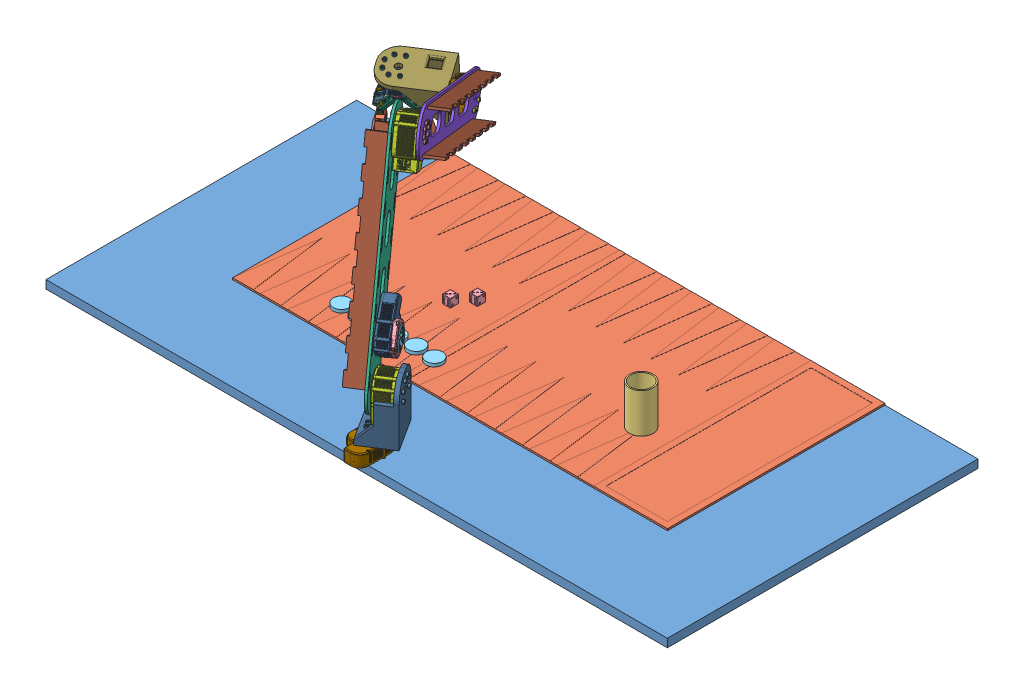
SolidWorks assembly Game Layout, configuration Default. Lengths in mm.
Overall size (1500 678.28 808.49).
129 component instances, 32 part files, 15 mates.
Components (placement in the parent):
- Table-1: Table [Default] at (-44.703 4.5181 13.7258) size (1500 20 750)
- Backgammon Board-1: Backgammon Board [Default] at (-44.703 25.1708 -98.7742) size (1050 4.19 525)
- Dice Cup-1: Dice Cup [Default] at (235.0542 28.3281 -18.6124) size (57.15 95.25 57.15)
- Die_20mm-1: Die_20mm [Default] at (-252.4545 38.3281 -45.2058) size (20 20 20)
- Die_20mm-2: Die_20mm [Default] at (-223.0507 38.3281 -81.2243) size (20 20 20)
- Checker_40mm-1: Checker_40mm [Default] at (-377.9375 28.7091 92.1875) size (40 7.5 40)
- Checker_40mm-2: Checker_40mm [Default] at (-334.5867 28.7091 91.8393) size (40 7.5 40)
- Checker_40mm-3: Checker_40mm [Default] at (-285.5011 28.7091 92.6533) size (40 7.5 40)
- Checker_40mm-4: Checker_40mm [Default] at (-245.1452 28.7091 92.2152) size (40 7.5 40)
- Checker_40mm-5: Checker_40mm [Default] at (-200.0358 28.7091 89.7421) size (40 7.5 40)
- Checker_40mm-6: Checker_40mm [Default] at (-153.1252 28.7091 92.7345) size (40 7.5 40)
- Full Arm-1: Full Arm [Default] at (-368.8864 329.5183 330.3626) x (-0.970024 0.122778 -0.209714) z (0.211313 0 -0.977418) size (657.6 592.09 574.41) (flexible)
  - Upper Arm Link Assembled-1: Upper Arm Link Assembled [Default] at (-318.6686 -146.2323 48.0705) size (548.93 592.09 574.41) (flexible)
    - ME134 Robot Upper Arm-1: ME134 Robot Upper Arm [Default] at (85.1585 219.3336 73.7726) x (0.402286 0.867288 0.293221) z (-0.70231 0.086885 0.706549) size (550 100 5.4)
    - HEBI Robotics-X8-Export-2021-1: HEBI Robotics-X8-Export-2021 [Default] at (-31.6742 11.4014 22.0613) x (-0.122778 -0.992434 0) z (0.70231 -0.086885 -0.706549) size (109.71 73.14 45.05)
    - HEBI Robotics-X8-Export-2021-3: HEBI Robotics-X8-Export-2021 [Default] at (148.6872 401.7633 154.6819) x (-0.402286 -0.867288 -0.293221) z (-0.70231 0.086885 0.706549) size (109.71 73.14 45.05)
    - ME134 Robot Lower Arm-2: ME134 Robot Lower Arm [Default] at (145.9078 392.6031 182.7675) x (0.57097 -0.524014 0.631983) z (-0.70231 0.086885 0.706549) size (550 100 5.4)
    - HEBI Robotics-X5-Export-1: HEBI Robotics-X5-Export [Default] at (401.4098 166.4784 443.3136) x (-0.57097 0.524014 -0.631983) z (0.70231 -0.086885 -0.706549) size (109.71 73.14 31.05)
    - ME134 Robot Base-1: ME134 Robot Base [Default] at (-45.0848 -151.804 61.3535) x (0.122778 0.992434 0) z (-0.70231 0.086885 0.706549) size (135 95 80)
    - HEBI Robotics-X5-Export-2: HEBI Robotics-X5-Export [Default] at (-33.2405 -99.2434 10.05) x (-0.209714 0.025945 -0.977418) z (0.122778 0.992434 0) size (109.71 73.14 31.05)
    - ME134 Arm Flange Short-1: ME134 Arm Flange Short [Default] at (-91.6967 -109.7229 -85.2577) x (0.402286 0.867288 0.293221) z (0.587305 -0.490167 0.644058) size (450 45.8 5.4)
    - ME134 Arm Flange Short-2: ME134 Arm Flange Short [Default] at (-42.0107 -151.191 -30.7704) x (0.402286 0.867288 0.293221) z (0.587305 -0.490167 0.644058) size (450 45.8 5.4)
    - ME134 Arm Flange Short-3: ME134 Arm Flange Short [Default] at (8.7558 456.2815 72.0864) x (0.57097 -0.524014 0.631983) z (-0.425152 -0.847266 -0.318411) size (450 45.8 5.4)
    - ME134 Arm Flange Short-4: ME134 Arm Flange Short [Default] at (482.8327 119.1985 584.7708) x (-0.57097 0.524014 -0.631983) z (0.425152 0.847266 0.318411) size (450 45.8 5.4)
  - Wrist-1: Wrist [Default] at (117.0927 26.9602 501.9879) x (0.711585 0.113815 0.69332) z (-0.020177 0.989695 -0.14176) size (95 153.99 205.81)
    - Wrist Bracket-1: Wrist Bracket [Default] at (0 -68.6171 35.5514) x (0 1 0) z (0 0 1) size (135 95 80)
    - Gripper-1: Gripper [Default] at (-36.5257 46.3543 -1.008) x (0 -1 0) z (1 0 0) size (132.13 195.81 73.14)
      - Hebi Motor with Gripper-1: Hebi Motor with Gripper [Default] at (-48.6457 -21.5594 3.9658) size (128.79 124.31 73.14)
        - HEBI Robotics-A-2143-02-1: HEBI Robotics-A-2143-02 [Default] at (0 4.6253 0) x (0.994658 0 0.103227) z (-0.103227 0 0.994658) size (112.08 105.21 45) (flexible)
          - HEBI Robotics-A-2143-02_PM-2357-02-1: HEBI Robotics-A-2143-02_PM-2357-02 [Default] at (0 30.9247 0) x (0 0 -1) z (1 0 0) size (45 28 44.67)
          - HEBI Robotics-A-2143-02_PM-2358-02-1: HEBI Robotics-A-2143-02_PM-2358-02 [Default] at (-30.4569 31.8574 0) x (0 0 -1) z (0.926102 -0.377274 0) size (23 26 33)
          - HEBI Robotics-A-2143-02_PM-2358-02-2: HEBI Robotics-A-2143-02_PM-2358-02 [Default] at (30.456 31.8595 0) x (0 0 1) z (-0.926098 -0.377283 0) size (23 26 33)
          - HEBI Robotics-A-2143-02_PM-2359-02-1: HEBI Robotics-A-2143-02_PM-2359-02 [Default] at (20.1262 54.8052 0) x (0 0 1) z (0.689702 0.724093 0) size (23 8 51.86)
          - HEBI Robotics-A-2143-02_PM-2359-02-2: HEBI Robotics-A-2143-02_PM-2359-02 [Default] at (-20.1272 54.8043 0) x (0 0 -1) z (-0.689746 0.724052 0) size (23 8 51.86)
          - HEBI Robotics-A-2143-02_PM-2360-02-1: HEBI Robotics-A-2143-02_PM-2360-02 [Default] at (-35.2543 70.6838 0) x (-1 -0.000026 0) z (0 0 -1) size (15.5 54 12.08)
          - HEBI Robotics-A-2143-02_PM-2360-02-2: HEBI Robotics-A-2143-02_PM-2360-02 [Default] at (35.2524 70.6856 0) x (1 0.000026 0) z (0 0 1) size (15.5 54 12.08)
          - HEBI Robotics-A-2055-01_PM-2218-01-1: HEBI Robotics-A-2055-01_PM-2218-01 [Default] at (0 11.4247 0) size (45 32.5 45)
          - HEBI Robotics-A-2055-01_PM-2221-01-1: HEBI Robotics-A-2055-01_PM-2221-01 [Default] at (12.5 22.9247 0) x (0.926098 0.377283 0) z (0 0 1) size (35.49 9.86 12)
          - HEBI Robotics-A-2055-01_PM-2221-01-2: HEBI Robotics-A-2055-01_PM-2221-01 [Default] at (-12.5 22.9247 0) x (-0.926154 0.377146 0) z (0 0 -1) size (35.49 9.86 12)
        - HEBI Robotics-X5-Export-2021-1: HEBI Robotics-X5-Export-2021 [Default] x (1 0 0) z (0 1 0) size (109.71 73.14 31.05)
      - gripper finger-1: gripper finger [Default] at (-55.6003 119.2497 -16.8634) x (0.994658 0 0.103227) z (0 -1 0) size (29.91 40 90)
      - gripper finger-2: gripper finger [Default] at (-41.6945 119.2515 24.7946) x (-0.994658 0 -0.103227) z (0 -1 0) size (29.91 40 90)
      - 91292A114_M3-0.5x12-1: 91292A114_M3-0.5x12 [91292A114] at (-83.795 82.7497 1.1223) x (-0.922369 -0.374262 -0.095725) z (0.103227 0 -0.994658) size (5.5 5.5 15.23)
      - 91292A114_M3-0.5x12-2: 91292A114_M3-0.5x12 [91292A114] at (-83.795 72.7497 1.1223) x (-0.860402 -0.501733 -0.089294) z (0.103227 0 -0.994658) size (5.5 5.5 15.23)
      - 91292A114_M3-0.5x12-4: 91292A114_M3-0.5x12 [91292A114] at (-83.6299 82.7497 -0.4692) x (-0.122616 -0.992373 -0.012725) z (-0.103227 0 0.994658) size (5.5 5.5 15.23)
      - 91292A114_M3-0.5x12-6: 91292A114_M3-0.5x12 [91292A114] at (-83.6299 72.7497 -0.4692) x (0.056962 -0.998359 0.005912) z (-0.103227 0 0.994658) size (5.5 5.5 15.23)
      - 91292A114_M3-0.5x12-8: 91292A114_M3-0.5x12 [91292A114] at (-13.4998 82.7515 6.809) x (0.237271 -0.971131 0.024624) z (-0.103227 0 0.994658) size (5.5 5.5 15.23)
      - 91292A114_M3-0.5x12-10: 91292A114_M3-0.5x12 [91292A114] at (-13.4998 72.7515 6.809) x (0.411818 -0.910263 0.042739) z (-0.103227 0 0.994658) size (5.5 5.5 15.23)
      - 91292A114_M3-0.5x12-12: 91292A114_M3-0.5x12 [91292A114] at (-13.6649 82.7515 8.4005) x (-0.731519 -0.677582 -0.075918) z (0.103227 0 -0.994658) size (5.5 5.5 15.23)
      - 91292A114_M3-0.5x12-14: 91292A114_M3-0.5x12 [91292A114] at (-13.6649 72.7515 8.4005) x (-0.785512 -0.613453 -0.081522) z (0.103227 0 -0.994658) size (5.5 5.5 15.23)
  - HEBI Gripper Spool-1: HEBI Gripper Spool [Default] at (-326.7715 -52.5562 101.7728) x (-0.622368 -0.55675 -0.55017) z (-0.345569 0.826124 -0.445086) size (109.71 43.69 73.67)
    - HEBI Robotics-Default (X5-9)_PM-2293-01-1: HEBI Robotics-Default (X5-9)_PM-2293-01 [Default] x (-1 0 0) z (0 0 -1) size (65.4 11.85 69.3)
    - HEBI Robotics-Default (X5-9)_PM-2292-01-1: HEBI Robotics-Default (X5-9)_PM-2292-01 [Default] at (0.0007 -3.95 0.0008) x (-1 0 0) z (0 0 -1) size (50 11 50)
    - HEBI Robotics-Default (X5-9)_PM-2290-01-1: HEBI Robotics-Default (X5-9)_PM-2290-01 [Default] at (-3.2493 3.55 -6.4992) x (-1 0 0) z (0 0 -1) size (15 7 25)
    - HEBI Robotics-Default (X5-9)_PP-2205-35-1: HEBI Robotics-Default (X5-9)_PP-2205-35 [Default] at (-18.09 -34.551 -30) x (0.92376 0 -0.382972) z (0 -1 0) size (5.5 5.5 38.26)
    - HEBI Robotics-Default (X5-9)_PP-2205-35-2: HEBI Robotics-Default (X5-9)_PP-2205-35 [Default] at (30 -34.551 14.91) x (0.92376 0 -0.382972) z (0 -1 0) size (5.5 5.5 38.26)
    - HEBI Robotics-Default (X5-9)_PP-2205-35-3: HEBI Robotics-Default (X5-9)_PP-2205-35 [Default] at (-15.79 -34.551 33.5) x (0.92376 0 -0.382972) z (0 -1 0) size (5.5 5.5 38.26)
    - HEBI Robotics-Default (X5-9)_PP-2205-35-4: HEBI Robotics-Default (X5-9)_PP-2205-35 [Default] at (30 -34.551 -14.91) x (0.92376 0 -0.382972) z (0 -1 0) size (5.5 5.5 38.26)
    - HEBI Robotics-Default (X5-9)_PP-2205-08-1: HEBI Robotics-Default (X5-9)_PP-2205-08 [Default] at (-6.7493 -2.45 -6.4992) x (0.940312 0 -0.340315) z (0 -1 0) size (5.5 5.5 11.2)
    - HEBI Robotics-Default (X5-9)_PP-2205-08-2: HEBI Robotics-Default (X5-9)_PP-2205-08 [Default] at (0.2507 -2.45 -14.9992) x (0.940312 0 -0.340315) z (0 -1 0) size (5.5 5.5 11.2)
    - HEBI Robotics-Default (X5-9)_PP-2205-08-3: HEBI Robotics-Default (X5-9)_PP-2205-08 [Default] at (0.2507 -2.45 2.0008) x (0.940312 0 -0.340315) z (0 -1 0) size (5.5 5.5 11.2)
    - HEBI Robotics-Default (X5-9)_PP-2131-12(PP-2131-12)-1: HEBI Robotics-Default (X5-9)_PP-2131-12(PP-2131-12) [Default] at (16.2542 -9.95 6.4871) x (-0.985138 0 -0.171764) z (0 -1 0) size (8.5 8.5 17.42)
    - HEBI Robotics-Default (X5-9)_PP-2131-12(PP-2131-12)-2: HEBI Robotics-Default (X5-9)_PP-2131-12(PP-2131-12) [Default] at (-16.0788 -9.95 6.9072) x (-0.985138 0 -0.171764) z (0 -1 0) size (8.5 8.5 17.42)
    - HEBI Robotics-Default (X5-9)_PP-2131-12(PP-2131-12)-3: HEBI Robotics-Default (X5-9)_PP-2131-12(PP-2131-12) [Default] at (16.0802 -9.95 -6.9057) x (-0.985138 0 -0.171764) z (0 -1 0) size (8.5 8.5 17.42)
    - HEBI Robotics-Default (X5-9)_PP-2131-12(PP-2131-12)-4: HEBI Robotics-Default (X5-9)_PP-2131-12(PP-2131-12) [Default] at (-16.2529 -9.95 -6.4855) x (-0.985138 0 -0.171764) z (0 -1 0) size (8.5 8.5 17.42)
    - HEBI Robotics-Default (X5-9)_X5-Export-1: HEBI Robotics-Default (X5-9)_X5-Export [Default] at (0.0007 -20 0.0008) x (-1 0 -0.000042) z (0 1 0) size (109.71 73.14 31.05)
    - HEBI Robotics-Default (X5-9)_PP-2241-01-1: HEBI Robotics-Default (X5-9)_PP-2241-01 [Default] at (20 0 23) x (0 -0.336423 -0.941711) z (0 -0.941711 0.336423) size (5.5 11 5.5)
  - 91292A191_M5-0.8x8-1: 91292A191_M5-0.8x8 [91292A191] at (79.6684 45.8499 502.7314) x (-0.665044 0.273953 -0.694742) z (0.70231 -0.086885 -0.706549) size (8.5 8.5 13.4)
  - 91292A191_M5-0.8x8-2: 91292A191_M5-0.8x8 [91292A191] at (91.0878 35.3697 515.371) x (-0.700921 0.089013 -0.707662) z (0.70231 -0.086885 -0.706549) size (8.5 8.5 13.4)
  - 91292A191_M5-0.8x8-3: 91292A191_M5-0.8x8 [91292A191] at (93.1293 16.1717 519.761) x (-0.711616 -0.059091 -0.70008) z (0.70231 -0.086885 -0.706549) size (8.5 8.5 13.4)
  - 91292A191_M5-0.8x8-4: 91292A191_M5-0.8x8 [91292A191] at (84.6262 -0.7736 513.3928) x (-0.709672 -0.163412 -0.685319) z (0.70231 -0.086885 -0.706549) size (8.5 8.5 13.4)
  - 91292A191_M5-0.8x8-5: 91292A191_M5-0.8x8 [91292A191] at (70.6805 -5.2991 500.0873) x (-0.705309 -0.219384 -0.6741) z (0.70231 -0.086885 -0.706549) size (8.5 8.5 13.4)
  - 91292A191_M5-0.8x8-6: 91292A191_M5-0.8x8 [91292A191] at (59.2611 5.1812 487.4476) x (-0.70504 -0.222066 -0.673502) z (0.70231 -0.086885 -0.706549) size (8.5 8.5 13.4)
  - 91292A124_M5-0.8x10-1: 91292A124_M5-0.8x10 [91292A124] at (-170.8017 267.1451 223.7202) x (-0.665044 0.273953 -0.694742) z (0.70231 -0.086885 -0.706549) size (8.5 8.5 15.41)
  - 91292A124_M5-0.8x10-2: 91292A124_M5-0.8x10 [91292A124] at (-169.4207 254.1578 226.69) x (-0.700921 0.089013 -0.707662) z (0.70231 -0.086885 -0.706549) size (8.5 8.5 15.41)
  - 91292A124_M5-0.8x10-3: 91292A124_M5-0.8x10 [91292A124] at (-175.1151 242.8096 222.4253) x (-0.711616 -0.059091 -0.70008) z (0.70231 -0.086885 -0.706549) size (8.5 8.5 15.41)
  - 91292A124_M5-0.8x10-4: 91292A124_M5-0.8x10 [91292A124] at (-184.5493 239.7481 213.4241) x (-0.709672 -0.163412 -0.685319) z (0.70231 -0.086885 -0.706549) size (8.5 8.5 15.41)
  - 91292A124_M5-0.8x10-5: 91292A124_M5-0.8x10 [91292A124] at (-192.1969 246.7667 204.9594) x (-0.705309 -0.219384 -0.6741) z (0.70231 -0.086885 -0.706549) size (8.5 8.5 15.41)
  - 91292A124_M5-0.8x10-6: 91292A124_M5-0.8x10 [91292A124] at (-193.5779 259.754 201.9896) x (-0.70504 -0.222066 -0.673502) z (0.70231 -0.086885 -0.706549) size (8.5 8.5 15.41)
  - 91292A124_M5-0.8x10-7: 91292A124_M5-0.8x10 [91292A124] at (-187.8835 271.1022 206.2544) x (-0.709572 -0.165151 -0.685006) z (0.70231 -0.086885 -0.706549) size (8.5 8.5 15.41)
  - 91292A124_M5-0.8x10-8: 91292A124_M5-0.8x10 [91292A124] at (-178.4493 274.1637 215.2555) x (-0.711253 -0.044289 -0.70154) z (0.70231 -0.086885 -0.706549) size (8.5 8.5 15.41)
  - 91292A124_M5-0.8x10-10: 91292A124_M5-0.8x10 [91292A124] at (-146.1819 235.23 202.8635) x (-0.497036 0.650691 -0.574071) z (-0.70231 0.086885 0.706549) size (8.5 8.5 15.41)
  - 91292A124_M5-0.8x10-12: 91292A124_M5-0.8x10 [91292A124] at (-166.3268 276.1037 177.8132) x (-0.583977 0.497281 -0.641625) z (-0.70231 0.086885 0.706549) size (8.5 8.5 15.41)
  - 91292A124_M5-0.8x10-13: 91292A124_M5-0.8x10 [91292A124] at (-152.4725 281.3834 190.9351) x (-0.637884 0.363792 -0.678793) z (-0.70231 0.086885 0.706549) size (8.5 8.5 15.41)
  - 91292A124_M5-0.8x10-14: 91292A124_M5-0.8x10 [91292A124] at (-140.7264 271.5801 203.8162) x (-0.667597 0.264179 -0.696078) z (-0.70231 0.086885 0.706549) size (8.5 8.5 15.41)
  - 91292A124_M5-0.8x10-15: 91292A124_M5-0.8x10 [91292A124] at (-138.1362 252.5758 208.7279) x (-0.680646 0.208775 -0.702235) z (-0.70231 0.086885 0.706549) size (8.5 8.5 15.41)
  - 91292A124_M5-0.8x10-16: 91292A124_M5-0.8x10 [91292A124] at (-174.3725 258.758 171.9488) x (-0.681219 0.206085 -0.702474) z (-0.70231 0.086885 0.706549) size (8.5 8.5 15.41)
  - 91292A124_M5-0.8x10-17: 91292A124_M5-0.8x10 [91292A124] at (-335.5166 -119.0423 58.2301) x (-0.668033 0.262478 -0.696303) z (-0.70231 0.086885 0.706549) size (8.5 8.5 15.41)
  - 91292A124_M5-0.8x10-18: 91292A124_M5-0.8x10 [91292A124] at (-344.8889 -122.6139 49.3532) x (-0.633112 0.37755 -0.675741) z (-0.70231 0.086885 0.706549) size (8.5 8.5 15.41)
  - 91292A124_M5-0.8x10-19: 91292A124_M5-0.8x10 [91292A124] at (-350.2771 -134.2303 45.4258) x (-0.565405 0.534965 -0.627798) z (-0.70231 0.086885 0.706549) size (8.5 8.5 15.41)
  - 91292A124_M5-0.8x10-20: 91292A124_M5-0.8x10 [91292A124] at (-327.6503 -125.6075 66.8566) x (-0.462795 0.698432 -0.545906) z (-0.70231 0.086885 0.706549) size (8.5 8.5 15.41)
  - 91292A124_M5-0.8x10-21: 91292A124_M5-0.8x10 [91292A124] at (-325.898 -138.4639 70.1793) x (-0.343124 0.828302 -0.442923) z (-0.70231 0.086885 0.706549) size (8.5 8.5 15.41)
  - 91292A124_M5-0.8x10-22: 91292A124_M5-0.8x10 [91292A124] at (-348.5248 -147.0867 48.7486) x (-0.236341 0.907769 -0.346553) z (-0.70231 0.086885 0.706549) size (8.5 8.5 15.41)
  - 91292A124_M5-0.8x10-23: 91292A124_M5-0.8x10 [91292A124] at (-340.6585 -153.6519 57.375) x (-0.165146 0.945561 -0.280432) z (-0.70231 0.086885 0.706549) size (8.5 8.5 15.41)
  - 91292A124_M5-0.8x10-24: 91292A124_M5-0.8x10 [91292A124] at (-331.2862 -150.0802 66.2519) x (-0.137495 0.957278 -0.254388) z (-0.70231 0.086885 0.706549) size (8.5 8.5 15.41)
  - 91292A058_M5-0.8x14-1: 91292A058_M5-0.8x14 [91292A058] at (-343.8996 -235.3828 41.9579) x (0.379908 -0.047 0.92383) z (-0.122778 -0.992434 0) size (8.5 8.5 19.43)
  - 91292A058_M5-0.8x14-2: 91292A058_M5-0.8x14 [91292A058] at (-334.5078 -236.5447 51.4363) x (0.560691 -0.069365 0.825114) z (-0.122778 -0.992434 0) size (8.5 8.5 19.43)
  - 91292A058_M5-0.8x14-3: 91292A058_M5-0.8x14 [91292A058] at (-334.5183 -236.5434 64.8302) x (0.732765 -0.090653 0.674416) z (-0.122778 -0.992434 0) size (8.5 8.5 19.43)
  - 91292A058_M5-0.8x14-4: 91292A058_M5-0.8x14 [91292A058] at (-343.925 -235.3796 74.2937) x (0.8725 -0.10794 0.476542) z (-0.122778 -0.992434 0) size (8.5 8.5 19.43)
  - 91292A058_M5-0.8x14-5: 91292A058_M5-0.8x14 [91292A058] at (-366.6094 -232.5733 64.8047) x (0.960279 -0.1188 0.252489) z (-0.122778 -0.992434 0) size (8.5 8.5 19.43)
  - 91292A058_M5-0.8x14-6: 91292A058_M5-0.8x14 [91292A058] at (-366.5989 -232.5746 51.4108) x (0.991864 -0.122707 0.033882) z (-0.122778 -0.992434 0) size (8.5 8.5 19.43)
  - 91292A058_M5-0.8x14-7: 91292A058_M5-0.8x14 [91292A058] at (-357.2175 -233.7352 74.2831) x (0.981189 -0.121387 -0.150109) z (-0.122778 -0.992434 0) size (8.5 8.5 19.43)
  - 91292A058_M5-0.8x14-8: 91292A058_M5-0.8x14 [91292A058] at (-357.1922 -233.7383 41.9473) x (0.95205 -0.117782 -0.282362) z (-0.122778 -0.992434 0) size (8.5 8.5 19.43)
  - 91292A058_M5-0.8x14-10: 91292A058_M5-0.8x14 [91292A058] at (-345.3845 -123.3529 100.5402) x (0.627146 0.545127 0.556349) z (0.70231 -0.086885 -0.706549) size (8.5 8.5 19.43)
  - 91292A058_M5-0.8x14-12: 91292A058_M5-0.8x14 [91292A058] at (-353.4825 -108.2443 90.6329) x (0.48725 0.782268 0.38813) z (0.70231 -0.086885 -0.706549) size (8.5 8.5 19.43)
  - 91292A058_M5-0.8x14-14: 91292A058_M5-0.8x14 [91292A058] at (-367.5066 -106.5093 76.4796) x (0.328497 0.920086 0.213382) z (0.70231 -0.086885 -0.706549) size (8.5 8.5 19.43)
  - 91292A058_M5-0.8x14-16: 91292A058_M5-0.8x14 [91292A058] at (-379.0423 -119.1889 66.5723) x (0.177135 0.982635 0.055237) z (0.70231 -0.086885 -0.706549) size (8.5 8.5 19.43)
  - 91292A058_M5-0.8x14-18: 91292A058_M5-0.8x14 [91292A058] at (-381.4979 -139.0376 66.5723) x (0.047366 0.996028 -0.075401) z (0.70231 -0.086885 -0.706549) size (8.5 8.5 19.43)
  - 91292A058_M5-0.8x14-20: 91292A058_M5-0.8x14 [91292A058] at (-347.8401 -143.2016 100.5402) x (-0.053805 0.983206 -0.174389) z (0.70231 -0.086885 -0.706549) size (8.5 8.5 19.43)
  - 91292A058_M5-0.8x14-22: 91292A058_M5-0.8x14 [91292A058] at (102.844 14.4113 495.0291) x (-0.711123 -0.040131 -0.701922) z (-0.70231 0.086885 0.706549) size (8.5 8.5 19.43)
  - 91292A058_M5-0.8x14-24: 91292A058_M5-0.8x14 [91292A058] at (102.5737 27.6672 493.1304) x (-0.699552 0.099611 -0.707605) z (-0.70231 0.086885 0.706549) size (8.5 8.5 19.43)
  - 91292A058_M5-0.8x14-26: 91292A058_M5-0.8x14 [91292A058] at (95.6433 35.9626 485.2214) x (-0.688321 0.170297 -0.705133) z (-0.70231 0.086885 0.706549) size (8.5 8.5 19.43)
  - 91292A058_M5-0.8x14-28: 91292A058_M5-0.8x14 [91292A058] at (96.2957 3.96 489.8053) x (-0.686175 0.181639 -0.704394) z (-0.70231 0.086885 0.706549) size (8.5 8.5 19.43)
  - 91292A058_M5-0.8x14-30: 91292A058_M5-0.8x14 [91292A058] at (86.7648 2.4356 480.5191) x (-0.693102 0.142949 -0.706523) z (-0.70231 0.086885 0.706549) size (8.5 8.5 19.43)
  - 91292A058_M5-0.8x14-32: 91292A058_M5-0.8x14 [91292A058] at (79.8343 10.731 472.6101) x (-0.704233 0.060205 -0.707412) z (-0.70231 0.086885 0.706549) size (8.5 8.5 19.43)
  - 91292A058_M5-0.8x14-34: 91292A058_M5-0.8x14 [91292A058] at (79.5641 23.9869 470.7114) x (-0.711685 -0.063003 -0.699668) z (-0.70231 0.086885 0.706549) size (8.5 8.5 19.43)
  - 91292A058_M5-0.8x14-36: 91292A058_M5-0.8x14 [91292A058] at (86.1124 34.4382 475.9351) x (-0.70492 -0.223248 -0.673237) z (-0.70231 0.086885 0.706549) size (8.5 8.5 19.43)
  - 91292A058_M5-0.8x14-38: 91292A058_M5-0.8x14 [91292A058] at (171.4659 49.6531 430.1106) x (0.764427 -0.076116 -0.640201) z (0.020177 -0.989695 0.14176) size (8.5 8.5 19.43)
  - 91292A058_M5-0.8x14-40: 91292A058_M5-0.8x14 [91292A058] at (185.5121 47.9154 415.9796) x (0.961841 -0.019482 -0.272915) z (0.020177 -0.989695 0.14176) size (8.5 8.5 19.43)
  - 91292A058_M5-0.8x14-42: 91292A058_M5-0.8x14 [91292A058] at (185.3823 45.1056 396.3815) x (0.989924 0.039652 0.135936) z (0.020177 -0.989695 0.14176) size (8.5 8.5 19.43)
  - 91292A058_M5-0.8x14-44: 91292A058_M5-0.8x14 [91292A058] at (171.1506 42.8293 382.5151) x (0.88245 0.084279 0.462795) z (0.020177 -0.989695 0.14176) size (8.5 8.5 19.43)
  - 91292A058_M5-0.8x14-46: 91292A058_M5-0.8x14 [91292A058] at (151.356 42.4523 382.7003) x (0.729905 0.111478 0.674397) z (0.020177 -0.989695 0.14176) size (8.5 8.5 19.43)
  - 91292A058_M5-0.8x14-48: 91292A058_M5-0.8x14 [91292A058] at (137.3098 44.19 396.8312) x (0.588799 0.126355 0.798342) z (0.020177 -0.989695 0.14176) size (8.5 8.5 19.43)
  - 91292A191_M5-0.8x8-8: 91292A191_M5-0.8x8 [91292A191] at (-287.1865 -71.9636 97.6503) x (0.230214 0.966911 0.10993) z (-0.70231 0.086885 0.706549) size (8.5 8.5 13.4)
  - 91292A191_M5-0.8x8-10: 91292A191_M5-0.8x8 [91292A191] at (-279.1408 -54.6178 103.5147) x (0.131235 0.991315 0.008544) z (-0.70231 0.086885 0.706549) size (8.5 8.5 13.4)
  - 91292A191_M5-0.8x8-12: 91292A191_M5-0.8x8 [91292A191] at (-315.3771 -48.4356 66.7355) x (0.481478 -0.673093 0.56136) z (-0.70231 0.086885 0.706549) size (8.5 8.5 13.4)
  - 91292A191_M5-0.8x8-14: 91292A191_M5-0.8x8 [91292A191] at (-307.3314 -31.0898 72.5999) x (0.060139 -0.981734 0.180504) z (-0.70231 0.086885 0.706549) size (8.5 8.5 13.4)
  - 91292A191_M5-0.8x8-16: 91292A191_M5-0.8x8 [91292A191] at (-301.0407 -77.2432 84.5284) x (-0.150432 0.951996 -0.266598) z (-0.70231 0.086885 0.706549) size (8.5 8.5 13.4)
  - 91292A191_M5-0.8x8-18: 91292A191_M5-0.8x8 [91292A191] at (-312.7868 -67.4399 71.6472) x (-0.23622 0.907843 -0.346442) z (-0.70231 0.086885 0.706549) size (8.5 8.5 13.4)
Mates (geometry in assembly coordinates):
- Coincident1: coincident anti-aligned: plane of Table-1 through (-44.703 24.5181 13.7258) normal (0 1 0); plane of Backgammon Board-1 through (-44.4401 24.5181 -98.7742) normal (0 -1 0)
- Coincident2: coincident aligned: plane of Table-1 through (-44.703 4.5181 13.7258) normal (1 0 0); plane of Backgammon Board-1 through (-44.703 25.1708 -98.7742) normal (1 0 0)
- Coincident3: coincident aligned: plane of Table-1 through (-794.703 24.5181 -361.2742) normal (0 0 -1); plane of Backgammon Board-1 through (-569.4401 28.3281 -361.2742) normal (0 0 -1)
- Coincident4: coincident anti-aligned: plane of Backgammon Board-1 through (-44.4401 28.3281 -98.7742) normal (0 1 0); plane of Die_20mm-1 through (-262.4545 28.3281 -35.2058) normal (0 -1 0)
- Coincident5: coincident anti-aligned: plane of Backgammon Board-1 through (-44.4401 28.3281 -98.7742) normal (0 1 0); plane of Die_20mm-2 through (-233.0507 28.3281 -71.2243) normal (0 -1 0)
- Coincident6: coincident anti-aligned: plane of Backgammon Board-1 through (-44.4401 28.7091 -98.7742) normal (0 1 0); plane of Checker_40mm-1 through (-377.9375 28.7091 92.1875) normal (0 -1 0)
- Coincident7: coincident anti-aligned: plane of Backgammon Board-1 through (-44.4401 28.7091 -98.7742) normal (0 1 0); plane of Checker_40mm-2 through (-334.5867 28.7091 91.8393) normal (0 -1 0)
- Coincident8: coincident anti-aligned: plane of Backgammon Board-1 through (-44.4401 28.7091 -98.7742) normal (0 1 0); plane of Checker_40mm-3 through (-285.5011 28.7091 92.6533) normal (0 -1 0)
- Coincident9: coincident anti-aligned: plane of Backgammon Board-1 through (-44.4401 28.7091 -98.7742) normal (0 1 0); plane of Checker_40mm-4 through (-245.1452 28.7091 92.2152) normal (0 -1 0)
- Coincident10: coincident anti-aligned: plane of Backgammon Board-1 through (-44.4401 28.7091 -98.7742) normal (0 1 0); plane of Checker_40mm-5 through (-200.0358 28.7091 89.7421) normal (0 -1 0)
- Coincident11: coincident anti-aligned: plane of Backgammon Board-1 through (-44.4401 28.7091 -98.7742) normal (0 1 0); plane of Checker_40mm-6 through (-153.1252 28.7091 92.7345) normal (0 -1 0)
- Coincident12: coincident anti-aligned: plane of Backgammon Board-1 through (-44.4401 28.3281 -98.7742) normal (0 1 0); plane of Dice Cup-1 through (235.0542 28.3281 -18.6124) normal (0 -1 0)
- Distance1: distance = 3.175 mm anti-aligned: plane of Full Arm-1/Upper Arm Link Assembled-1/HEBI Robotics-X5-Export-2 through (-44.703 27.6931 340.9861) normal (0 -1 0); plane of Table-1 through (-44.703 24.5181 13.7258) normal (0 1 0)
- Width1: width aligned: plane of Full Arm-1/Upper Arm Link Assembled-1/HEBI Robotics-X5-Export-2 through (-77.703 32.6931 340.9861) normal (-1 0 0); plane of Table-1 through (-11.703 32.6931 340.9861) normal (1 0 0); plane of Full Arm-1/Upper Arm Link Assembled-1/HEBI Robotics-X5-Export-2 through (-794.703 24.5181 388.7258) normal (-1 0 0); plane of Table-1 through (705.297 24.5181 388.7258) normal (1 0 0)
- Distance2: distance = 25.4 mm aligned: plane of Table-1 through (-794.703 24.5181 388.7258) normal (0 0 1); plane of Full Arm-1/Upper Arm Link Assembled-1/HEBI Robotics-X5-Export-2 through (-33.703 32.6931 414.1258) normal (0 0 1)
